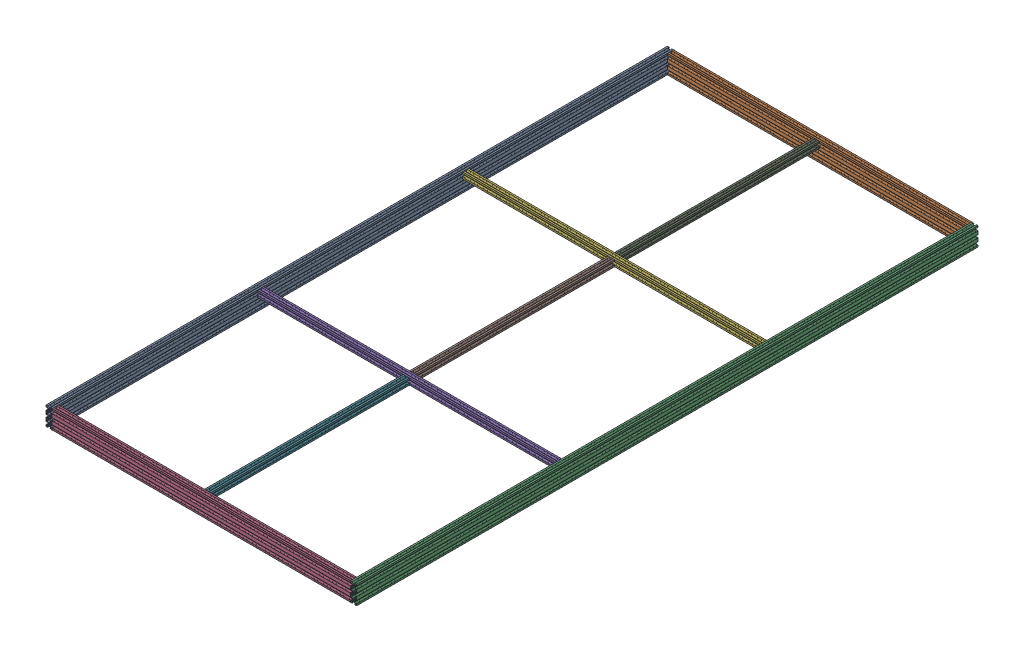
SolidWorks assembly Tiers_De_Table, configuration Défaut. Lengths in mm.
Overall size (1000 60 2000).
9 component instances, 4 part files, 25 mates.
Components (placement in the parent):
- Profile_20mm_60mm_2000mm-1: Profile_20mm_60mm_2000mm [Défaut] at origin size (20 60 2000)
- Profile_20mm_60mm_960mm-1: Profile_20mm_60mm_960mm [Défaut] at (12.5135 0 12.5135) x (0 0 -1) z (1 0 0) size (20 60 960)
- Profile_20mm_60mm_2000mm-2: Profile_20mm_60mm_2000mm [Défaut] at (980 0 0) size (20 60 2000)
- Profile_20mm_60mm_960mm-2: Profile_20mm_60mm_960mm [Défaut] at (12.5135 0 1992.5135) x (0 0 -1) z (1 0 0) size (20 60 960)
- Profile_20mm_20mm_960mm-1: Profile_20mm_20mm_960mm [Défaut] at (12.5135 19.2685 1340.5749) x (0 0 -1) z (1 0 0) size (20 20 960)
- Profile_20mm_20mm_960mm-2: Profile_20mm_20mm_960mm [Défaut] at (12.5135 19.2685 680.5749) x (0 0 -1) z (1 0 0) size (20 20 960)
- Profile_20mm_20mm_640mm-3: Profile_20mm_20mm_640mm [Défaut] at (481.9386 19.2685 1340) size (20 20 640)
- Profile_20mm_20mm_640mm-4: Profile_20mm_20mm_640mm [Défaut] at (481.9386 19.2685 680) size (20 20 640)
- Profile_20mm_20mm_640mm-5: Profile_20mm_20mm_640mm [Défaut] at (481.9386 19.2685 20) size (20 20 640)
Mates (geometry in assembly coordinates):
- Coïncidente1: coincident aligned: plane of Profile_20mm_60mm_2000mm-1 through (-2.3693 29.5733 2000) normal (0 1 0); plane of Profile_20mm_60mm_960mm-2 through (972.5135 29.5733 1994.8828) normal (0 1 0)
- Coïncidente2: coincident aligned: plane of Profile_20mm_60mm_2000mm-1 through (12.2135 29.5733 2000) normal (0 1 0); plane of Profile_20mm_60mm_960mm-1 through (972.5135 29.5733 14.8828) normal (0 1 0)
- Coïncidente3: coincident aligned: plane of Profile_20mm_60mm_960mm-1 through (972.5135 29.5733 0.3) normal (0 1 0); plane of Profile_20mm_60mm_2000mm-2 through (977.6307 29.5733 2000) normal (0 1 0)
- Coïncidente4: coincident anti-aligned: plane of Profile_20mm_60mm_960mm-1 through (972.5135 -15.2273 17.9) normal (1 0 0); plane of Profile_20mm_60mm_2000mm-2 through (972.5135 9.5733 2000) normal (-1 0 0)
- Coïncidente5: coincident aligned: plane of Profile_20mm_60mm_960mm-1 through (972.5135 9.5733 0) normal (0 0 -1); plane of Profile_20mm_60mm_2000mm-2 through (974.6135 -15.2273 0) normal (0 0 -1)
- Coïncidente6: coincident aligned: plane of Profile_20mm_60mm_2000mm-1 through (-5.3865 -15.2273 0) normal (0 0 -1); plane of Profile_20mm_60mm_960mm-1 through (972.5135 -10.4267 0) normal (0 0 -1)
- Coïncidente7: coincident anti-aligned: plane of Profile_20mm_60mm_2000mm-1 through (12.5135 9.5733 2000) normal (1 0 0); plane of Profile_20mm_60mm_960mm-1 through (12.5135 -15.2273 17.9) normal (-1 0 0)
- Coïncidente8: coincident anti-aligned: plane of Profile_20mm_60mm_2000mm-1 through (12.5135 9.5733 2000) normal (1 0 0); plane of Profile_20mm_60mm_960mm-2 through (12.5135 -15.2273 1997.9) normal (-1 0 0)
- Coïncidente9: coincident aligned: plane of Profile_20mm_60mm_2000mm-1 through (-5.3865 -15.2273 2000) normal (0 0 1); plane of Profile_20mm_60mm_960mm-2 through (972.5135 -10.4267 2000) normal (0 0 1)
- Coïncidente11: coincident aligned: plane of Profile_20mm_60mm_2000mm-1 through (-2.3693 29.5733 2000) normal (0 1 0); plane of Profile_20mm_20mm_960mm-1 through (972.5135 29.5733 1334.8828) normal (0 1 0)
- Coïncidente16: coincident anti-aligned: plane of Profile_20mm_60mm_2000mm-2 through (972.5135 9.5733 2000) normal (-1 0 0); plane of Profile_20mm_20mm_960mm-1 through (972.5135 16.3733 1321.7) normal (1 0 0)
- Coïncidente19: coincident aligned: plane of Profile_20mm_60mm_2000mm-1 through (12.2135 29.5733 2000) normal (0 1 0); plane of Profile_20mm_20mm_960mm-2 through (972.5135 29.5733 674.8828) normal (0 1 0)
- Coïncidente22: coincident anti-aligned: plane of Profile_20mm_60mm_2000mm-1 through (12.5135 9.5733 2000) normal (1 0 0); plane of Profile_20mm_20mm_960mm-2 through (12.5135 16.3733 661.7) normal (-1 0 0)
- Coïncidente26: coincident anti-aligned: plane of Profile_20mm_60mm_960mm-2 through (972.5135 9.5733 1980) normal (0 0 -1); plane of Profile_20mm_20mm_970mm-3 through (499.5507 16.3733 1980) normal (0 0 1)
- Coïncidente27: coincident aligned: plane of Profile_20mm_60mm_960mm-2 through (972.5135 29.5733 1980.3) normal (0 1 0); plane of Profile_20mm_20mm_970mm-3 through (486.3679 29.5733 1980) normal (0 1 0)
- Coïncidente28: coincident anti-aligned: plane of Profile_20mm_20mm_960mm-1 through (972.5135 29.2733 1340) normal (0 0 1); plane of Profile_20mm_20mm_970mm-3 through (499.5507 16.3733 1340) normal (0 0 -1)
- Coïncidente29: coincident aligned: plane of Profile_20mm_20mm_970mm-3 through (486.3679 29.5733 1980) normal (0 1 0); plane of Profile_20mm_20mm_970mm-4 through (486.3679 29.5733 1320) normal (0 1 0)
- Coïncidente30: coincident aligned: plane of Profile_20mm_20mm_970mm-3 through (486.3679 29.5733 1980) normal (0 1 0); plane of Profile_20mm_20mm_970mm-5 through (486.3679 29.5733 660) normal (0 1 0)
- Coïncidente31: coincident anti-aligned: plane of Profile_20mm_60mm_960mm-1 through (972.5135 9.5733 20) normal (0 0 1); plane of Profile_20mm_20mm_970mm-5 through (499.5507 16.3733 20) normal (0 0 -1)
- Coïncidente32: coincident anti-aligned: plane of Profile_20mm_20mm_960mm-2 through (972.5135 9.8733 660) normal (0 0 -1); plane of Profile_20mm_20mm_970mm-5 through (499.5507 16.3733 660) normal (0 0 1)
- Coïncidente33: coincident anti-aligned: plane of Profile_20mm_20mm_960mm-2 through (972.5135 29.2733 680) normal (0 0 1); plane of Profile_20mm_20mm_970mm-4 through (499.5507 16.3733 680) normal (0 0 -1)
- Coïncidente34: coincident anti-aligned: plane of Profile_20mm_20mm_960mm-1 through (972.5135 9.8733 1320) normal (0 0 -1); plane of Profile_20mm_20mm_970mm-4 through (499.5507 16.3733 1320) normal (0 0 1)
- Coïncidente35: coincident aligned: plane of Profile_20mm_20mm_970mm-3 through (501.2507 24.4562 1980) normal (1 0 0); plane of Profile_20mm_20mm_970mm-4 through (501.2507 24.4562 1320) normal (1 0 0)
- Coïncidente36: coincident aligned: plane of Profile_20mm_20mm_970mm-4 through (501.2507 24.4562 1320) normal (1 0 0); plane of Profile_20mm_20mm_970mm-5 through (501.2507 24.4562 660) normal (1 0 0)
- Distance2: distance = 470 mm anti-aligned: plane of Profile_20mm_20mm_970mm-3 through (502.5135 24.4562 1980) normal (1 0 0); plane of Profile_20mm_60mm_2000mm-2 through (972.5135 -10.4267 2000) normal (-1 0 0)
